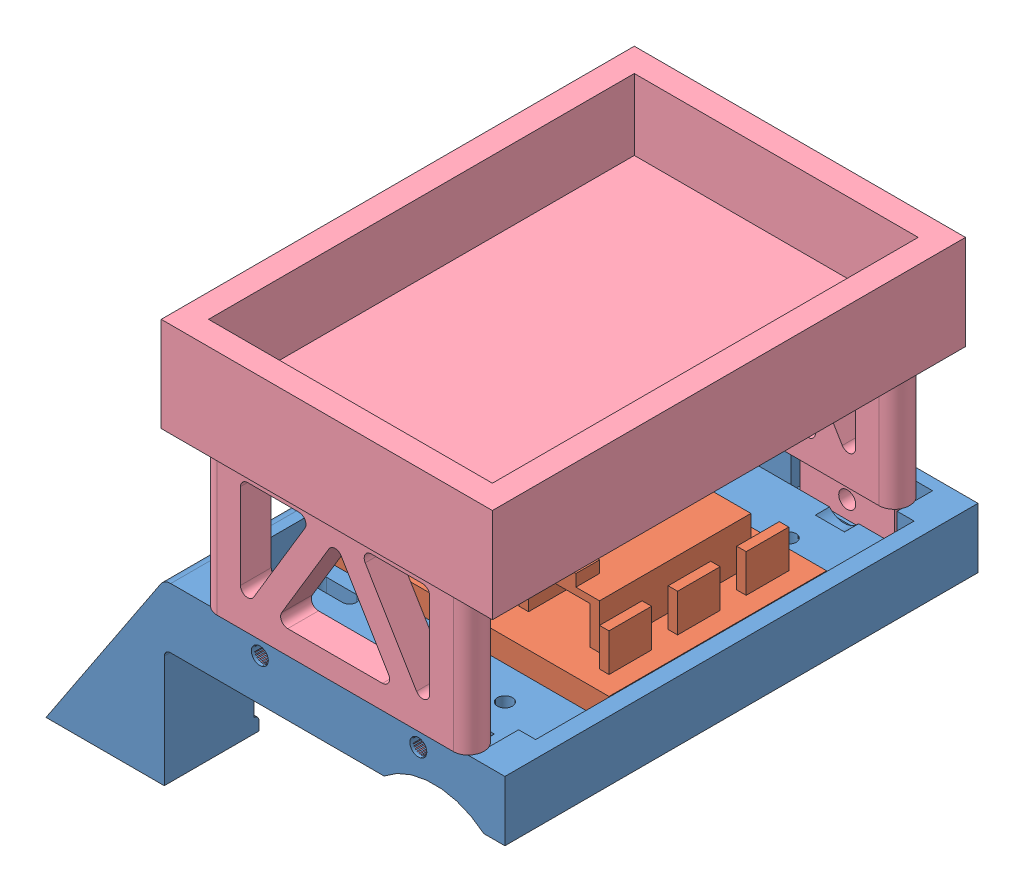
SolidWorks assembly Full Bot, configuration Default. Lengths in mm.
Overall size (97 87.65 102.59).
4 component instances, 4 part files, 7 mates.
Components (placement in the parent):
- Plow Rev 1-1: Plow Rev 1 [Default] at origin size (97 37.7 100)
- Protoboard-1: Protoboard [Default] at (-3.8506 -6.35 -30.8954) size (62 17 46)
- Caster Wheel-1: Caster Wheel [Default] at (-43.5187 -30.888 -23.1783) x (0 0 1) z (-1 0 0) size (18.73 13 14.73)
- Battery Holder-1: Battery Holder [Default] at (28.852 -7.55 -42.0363) size (70 57.5 100)
Mates (geometry in assembly coordinates):
- Coincident1: coincident anti-aligned: plane of Plow Rev 1-1 through (0 -6.35 0) normal (0 1 0); plane of Protoboard-1 through (-3.8506 -6.35 -30.8954) normal (0 -1 0)
- Width2: width anti-aligned: plane of Plow Rev 1-1 through (-31.9822 -6.35 16.8217) normal (0 0 -1); plane of Plow Rev 1-1 through (-31.9822 -6.35 -63.1783) normal (0 0 1); plane of Protoboard-1 through (-30.4822 -1.35 -0.1783) normal (0 0 1); plane of Protoboard-1 through (-30.4822 -1.35 -46.1783) normal (0 0 -1)
- Width3: width anti-aligned: plane of Plow Rev 1-1 through (-31.9822 -6.35 -63.1783) normal (1 0 0); plane of Plow Rev 1-1 through (33.0178 -6.35 -63.1783) normal (-1 0 0); plane of Protoboard-1 through (-30.4822 -1.35 -46.1783) normal (-1 0 0); plane of Protoboard-1 through (31.5178 -1.35 -46.1783) normal (1 0 0)
- Concentric4: concentric anti-aligned: cylinder of Plow Rev 1-1 through (-43.5187 -26.7 -30.5443) axis (0 -1 0) radius 1.786; circle of Caster Wheel-1
- Concentric7: concentric aligned: cylinder of Plow Rev 1-1 through (-43.5187 -26.7 -15.8123) axis (0 -1 0) radius 1.786; cylinder of Caster Wheel-1 through (-43.5187 -24.238 -15.8123) axis (0 -1 0) radius 1
- Concentric8: concentric aligned: cylinder of Plow Rev 1-1 through (18.2178 -3.8 -78.2695) axis (0 0 1) radius 1.8; cylinder of Battery Holder-1 through (18.2178 -3.8 -72.4252) axis (0 0 1) radius 1.8
- Concentric9: concentric aligned: cylinder of Plow Rev 1-1 through (-15.2822 -3.8 -78.2695) axis (0 0 1) radius 1.8; cylinder of Battery Holder-1 through (-15.2822 -3.8 -72.4252) axis (0 0 1) radius 1.8
